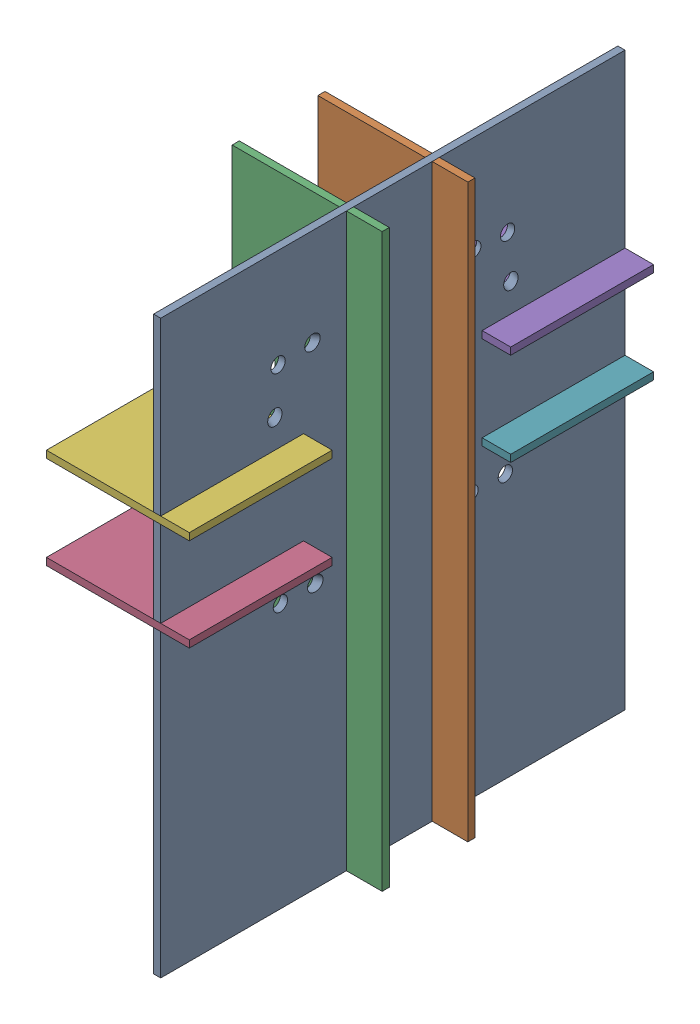
SolidWorks assembly Yellow Jig Assembly, configuration Default. Lengths in mm.
Overall size (2676.2 1667.85 825.5).
8 component instances, 8 part files, 21 mates.
Components (placement in the parent):
- University_of_Portland_Chassis_006-1: University_of_Portland_Chassis_006 [Default<As Machined>] at origin (suppressed, hidden)
- Yellow_1-1: Yellow_1 [Default] at (133.35 -469.9 0) size (12.7 1016 825.5)
- Yellow_2-1: Yellow_2 [Default] at (69.85 -469.9 -76.2) size (266.7 1016 12.7)
- Yellow_3-1: Yellow_3 [Default] at (69.85 -469.9 76.2) size (266.7 1016 12.7)
- Yellow_4-1: Yellow_4 [Default] at (190.5 69.85 285.75) x (0 0 -1) z (1 0 0) size (254 12.7 254)
- Yellow_5-3: Yellow_5 [Default] at (190.5 234.95 -285.75) x (0 0 -1) z (1 0 0) size (254 12.7 254)
- Yellow_6-2: Yellow_6 [Default] at (63.5 234.95 412.75) size (254 12.7 254)
- Yellow_7-2: Yellow_7 [Default] at (63.5 69.85 -158.75) size (254 12.7 254)
Mates (geometry in assembly coordinates):
- Coincident3: coincident aligned: plane of Yellow_1-1 through (139.7 -469.9 412.75) normal (0 -1 0)
- Distance1: distance = 139.7 mm aligned: plane of Yellow_1-1 through (127 -469.9 0) normal (-1 0 0)
- Symmetric2: symmetric aligned: plane of Yellow_1-1 through (139.7 -469.9 -412.75) normal (0 0 -1); plane of Yellow_1-1 through (139.7 -469.9 412.75) normal (0 0 1)
- Coincident2: coincident aligned: plane of Yellow_2-1 through (-63.5 -469.9 -69.85) normal (0 -1 0)
- Distance2: distance = 330.2 mm aligned: plane of Yellow_2-1 through (69.85 -469.9 -82.55) normal (0 0 -1); plane of Yellow_1-1 through (139.7 -469.9 -412.75) normal (0 0 -1)
- Distance3: distance = 50.8 mm: plane of assembly through (-12.7 0 0) normal (-1 0 0); plane of assembly; plane of Yellow_2-1 through (-63.5 -469.9 -69.85) normal (-1 0 0)
- Coincident4: coincident aligned: plane of Yellow_3-1 through (-63.5 -469.9 82.55) normal (0 -1 0)
- Distance4: distance = 330.2 mm aligned: plane of Yellow_3-1 through (69.85 -469.9 82.55) normal (0 0 1); plane of Yellow_1-1 through (139.7 -469.9 412.75) normal (0 0 1)
- Coincident6: coincident aligned: plane of Yellow_2-1 through (-63.5 -469.9 -69.85) normal (-1 0 0); plane of Yellow_3-1 through (-63.5 -469.9 82.55) normal (-1 0 0)
- Coincident7: coincident aligned: plane of Yellow_1-1 through (139.7 -469.9 -412.75) normal (0 0 -1); plane of Yellow_5-3 through (190.5 241.3 -412.75) normal (0 0 -1)
- Coincident8: coincident aligned: plane of Yellow_2-1 through (-63.5 -469.9 -69.85) normal (-1 0 0); plane of Yellow_5-3 through (-63.5 241.3 -158.75) normal (-1 0 0)
- Coincident9: coincident aligned: plane of Yellow_1-1 through (139.7 -469.9 412.75) normal (0 0 1); plane of Yellow_4-1 through (190.5 76.2 412.75) normal (0 0 1)
- Coincident13: coincident aligned: plane of Yellow_3-1 through (-63.5 -469.9 82.55) normal (-1 0 0); plane of Yellow_4-1 through (-63.5 76.2 412.75) normal (-1 0 0)
- Coincident14: coincident aligned: plane of Yellow_1-1 through (139.7 -469.9 -412.75) normal (0 0 -1); plane of Yellow_7-2 through (-63.5 76.2 -412.75) normal (0 0 -1)
- Coincident15: coincident aligned: plane of Yellow_5-3 through (-63.5 241.3 -158.75) normal (-1 0 0); plane of Yellow_7-2 through (-63.5 76.2 -158.75) normal (-1 0 0)
- Coincident16: coincident aligned: plane of Yellow_1-1 through (139.7 -469.9 412.75) normal (0 0 1); plane of Yellow_6-2 through (-63.5 241.3 412.75) normal (0 0 1)
- Coincident17: coincident aligned: plane of Yellow_4-1 through (-63.5 76.2 412.75) normal (-1 0 0); plane of Yellow_6-2 through (-63.5 241.3 412.75) normal (-1 0 0)
- Distance7: distance = 152.4 mm anti-aligned: plane of Yellow_4-1 through (190.5 76.2 285.75) normal (0 1 0); plane of Yellow_6-2 through (63.5 228.6 412.75) normal (0 -1 0)
- Distance10: distance = 304.8 mm aligned: plane of Yellow_6-2 through (63.5 241.3 412.75) normal (0 1 0); plane of Yellow_1-1 through (139.7 546.1 412.75) normal (0 1 0)
- Coincident18: coincident aligned: plane of Yellow_5-3 through (190.5 241.3 -285.75) normal (0 1 0); plane of Yellow_6-2 through (63.5 241.3 412.75) normal (0 1 0)
- Coincident19: coincident aligned: plane of Yellow_4-1 through (190.5 76.2 285.75) normal (0 1 0); plane of Yellow_7-2 through (63.5 76.2 -158.75) normal (0 1 0)
